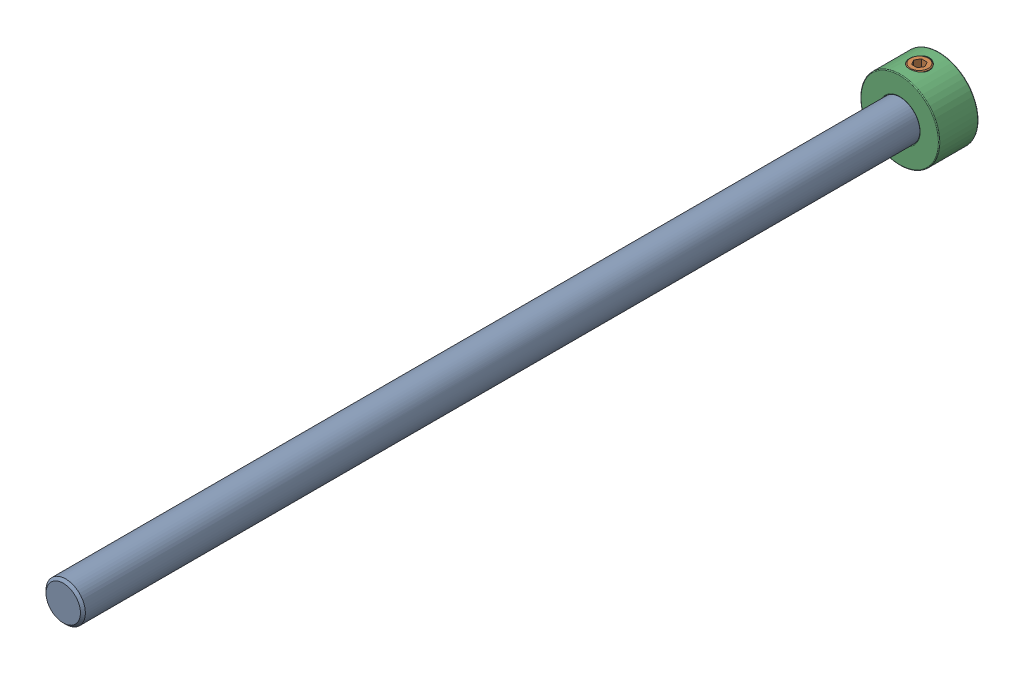
SolidWorks assembly SSDCT Guide Rod Asmbly, configuration Default. Lengths in mm.
Overall size (16 16 180).
2 component instances, 2 part files, 0 mates.
Components (placement in the parent):
- SSDCT 8mm x 180mm Rod-1: SSDCT 8mm x 180mm Rod [Default] at origin size (8 8 180)
- 57485K67-1: 57485K67 [57485K67] at (-26 0 18) size (16 16 8)
